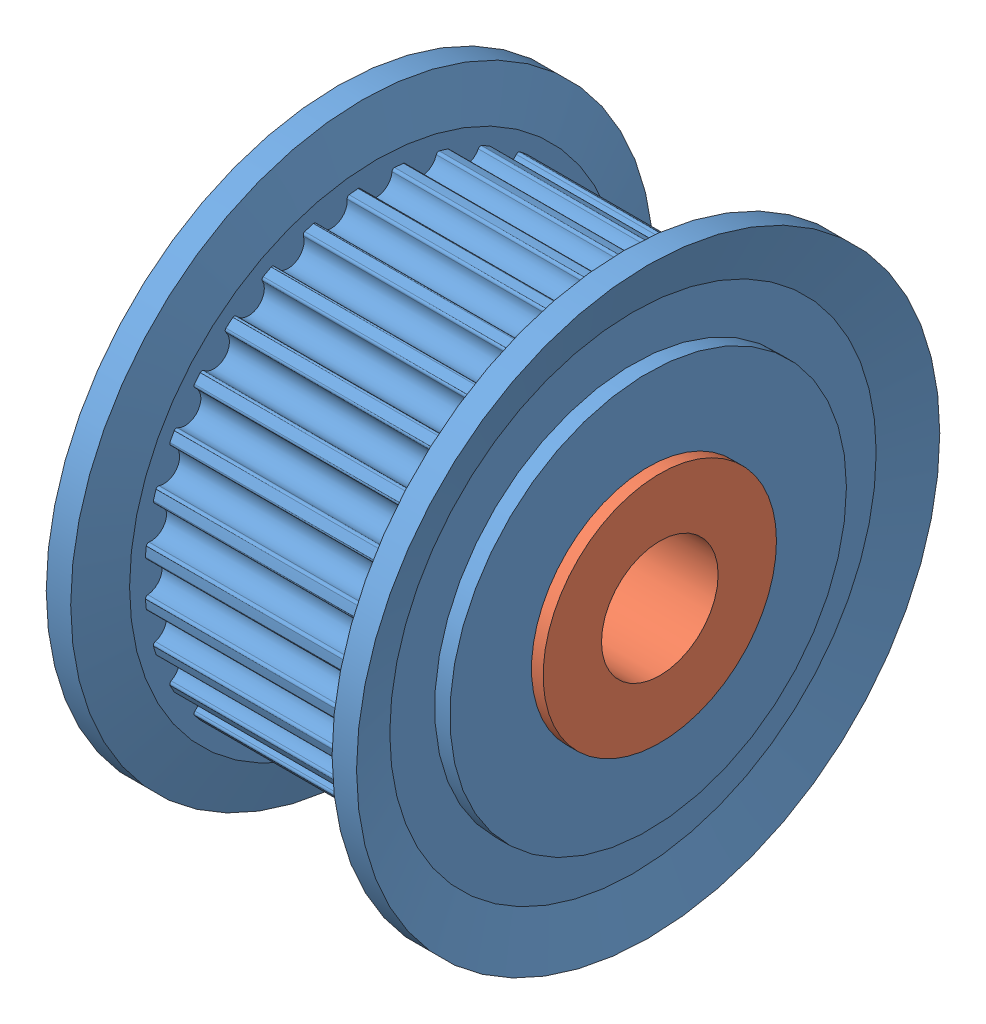
SolidWorks assembly Y Idler, configuration Default. Lengths in mm.
Overall size (14.3 25 25).
3 component instances, 2 part files, 4 mates.
Components (placement in the parent):
- Y Axis Idlergpa32gt2090_a_h6_2_03-1: Y Axis Idlergpa32gt2090_a_h6_2_03 [Default] at (-0.0026 20.6312 18.9623) size (13.3 25 25)
- GFM-0506-06-1: GFM-0506-06 [Default] at (7.1474 20.6312 18.9623) x (0 0 1) z (-1 0 0) size (10 10 6)
- GFM-0506-06-2: GFM-0506-06 [Default] at (-7.1526 20.6312 18.9623) x (0 0 -1) z (1 0 0) size (10 10 6)
Mates (geometry in assembly coordinates):
- Coincident1: coincident anti-aligned: plane of Y Axis Idlergpa32gt2090_a_h6_2_03-1 through (6.6474 24.8812 18.9623) normal (1 0 0); plane of GFM-0506-06-1 through (6.6474 20.6312 23.2123) normal (-1 0 0)
- Concentric1: concentric aligned: cylinder of Y Axis Idlergpa32gt2090_a_h6_2_03-1 through (-0.0026 20.6312 18.9623) axis (1 0 0) radius 3; circle of GFM-0506-06-1
- Coincident2: coincident anti-aligned: plane of Y Axis Idlergpa32gt2090_a_h6_2_03-1 through (-6.6526 24.8812 18.9623) normal (-1 0 0); plane of GFM-0506-06-2 through (-6.6526 20.6312 14.7123) normal (1 0 0)
- Concentric2: concentric anti-aligned: cylinder of Y Axis Idlergpa32gt2090_a_h6_2_03-1 through (-0.0026 20.6312 18.9623) axis (1 0 0) radius 3; cylinder of GFM-0506-06-2 through (-4.1526 20.6312 18.9623) axis (-1 0 0) radius 2.5
